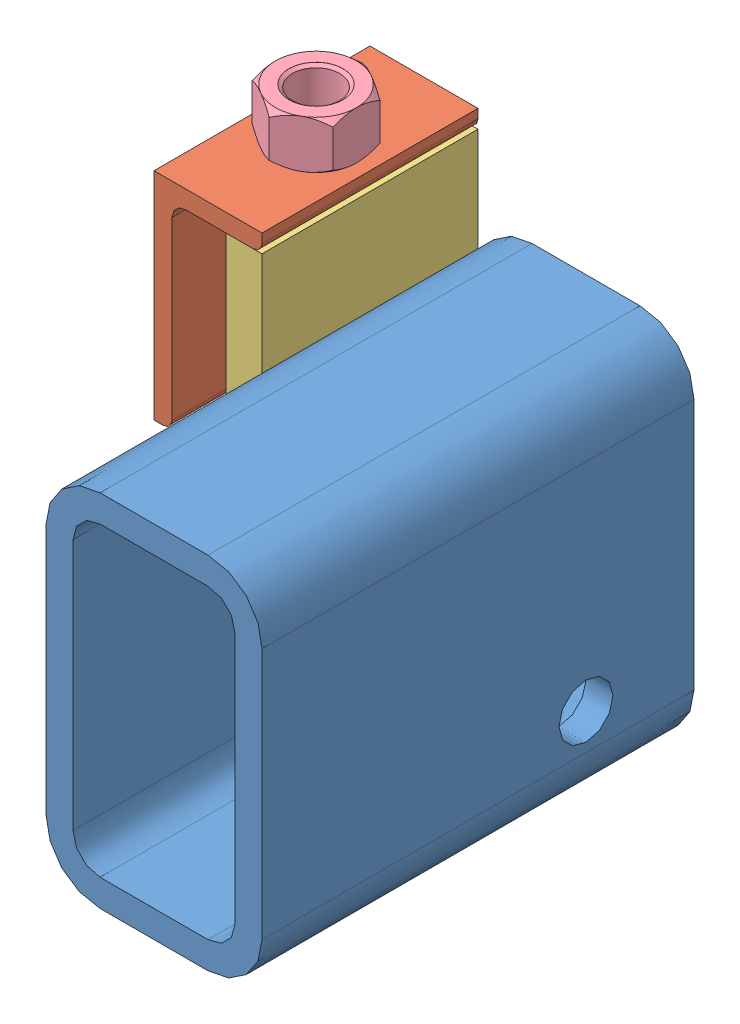
SolidWorks assembly drawer support ass_2, configuration Default. Lengths in mm.
Overall size (131.19 175.64 152.4).
5 component instances, 4 part files, 10 mates.
Components (placement in the parent):
- tube rectangular_Drawer support_2-1: tube rectangular_Drawer support_2 [PreviewCfg] at (-77.1568 -52.5968 13.2023) size (76.2 127 152.4)
- drawer support angle-1: drawer support angle [PreviewCfg] at (-115.2568 106.1532 -24.8977) x (1 0 0) z (0 0 -1) size (38.1 76.2 76.2)
- drawer support member-1: drawer support member [Default] at (-89.8568 99.8032 -62.9977) x (0 -1 0) z (0 0 1) size (127 12.7 76.2)
- hex nut_ai-1: hex nut_ai [HNUT 0.7500-10-D-C] at (-115.2568 49.0032 -24.8977) x (0 0 -1) z (1 0 0) size (28.57 33 16.89)
- hex nut_ai-2: hex nut_ai [HNUT 0.7500-10-D-C] at (-96.2068 106.1532 -24.8977) x (1 0 0) z (0 -1 0) size (28.57 33 16.89)
Mates (geometry in assembly coordinates):
- Coincident1: coincident anti-aligned: plane of tube rectangular_Drawer support_2-1 through (-77.1568 -33.5468 89.4023) normal (-1 0 0); plane of drawer support member-1 through (-77.1568 99.8032 -62.9977) normal (1 0 0)
- Distance1: distance = 25.4 mm aligned: plane of drawer support member-1 through (-77.1568 -27.1968 -62.9977) normal (0 -1 0); plane of tube rectangular_Drawer support_2-1 through (-58.1068 -52.5968 89.4023) normal (0 -1 0)
- Coincident3: coincident aligned: plane of tube rectangular_Drawer support_2-1 through (-20.0068 55.3532 -62.9977) normal (0 0 -1); plane of drawer support member-1 through (-77.1568 99.8032 -62.9977) normal (0 0 -1)
- Coincident4: coincident aligned: plane of drawer support angle-1 through (-77.1568 102.9731 -62.9977) normal (1 0 0); plane of drawer support member-1 through (-77.1568 99.8032 -62.9977) normal (1 0 0)
- Coincident5: coincident anti-aligned: plane of drawer support angle-1 through (-104.1443 99.8032 -62.9977) normal (0 -1 0); plane of drawer support member-1 through (-77.1568 99.8032 -62.9977) normal (0 1 0)
- Coincident6: coincident aligned: plane of drawer support angle-1 through (-112.0768 33.1231 -62.9977) normal (0 0 -1); plane of drawer support member-1 through (-77.1568 99.8032 -62.9977) normal (0 0 -1)
- Concentric1: concentric anti-aligned: cylinder of drawer support angle-1 through (-77.1568 49.0032 -24.8977) axis (-1 0 0) radius 6.35; cylinder of hex nut_ai-1 through (-132.1478 49.0032 -24.8977) axis (1 0 0) radius 8.3337
- Coincident7: coincident anti-aligned: plane of drawer support angle-1 through (-115.2568 106.1532 -62.9977) normal (-1 0 0); plane of hex nut_ai-1 through (-115.2568 65.501 -24.8977) normal (1 0 0)
- Concentric2: concentric anti-aligned: cylinder of drawer support angle-1 through (-96.2068 29.9522 -24.8977) axis (0 1 0) radius 6.35; cylinder of hex nut_ai-2 through (-96.2068 123.0442 -24.8977) axis (0 -1 0) radius 8.3337
- Coincident8: coincident anti-aligned: plane of drawer support angle-1 through (-77.1568 106.1532 -62.9977) normal (0 1 0); plane of hex nut_ai-2 through (-96.2068 106.1532 -8.3999) normal (0 -1 0)
